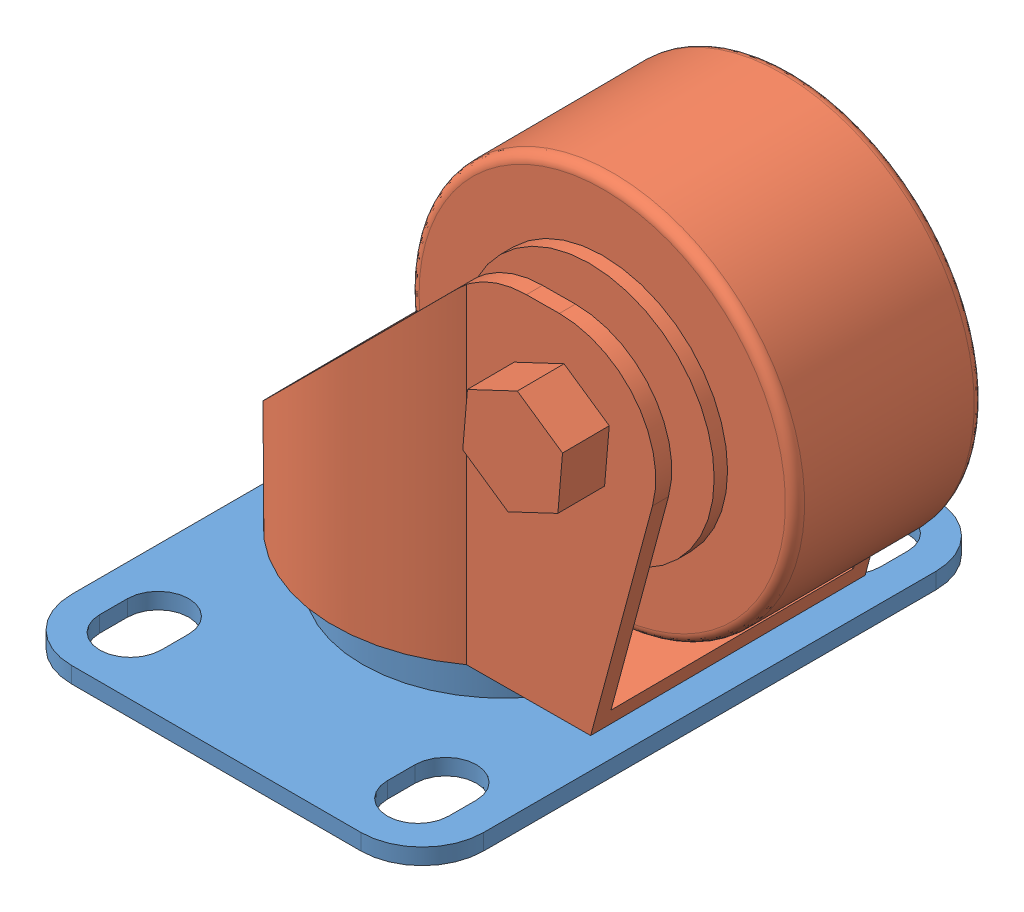
SolidWorks assembly MACM010210_UniversalWheel, configuration 默认. Lengths in mm.
Overall size (61.61 53.2 60).
2 component instances, 2 part files, 2 mates.
Components (placement in the parent):
- MACM010211_UniversalWheelA_1.5inch-1: MACM010211_UniversalWheelA_1.5inch [默认] at (-2.179 -1.6848 60) size (43 6.68 60)
- MACM010212_UniversalWheelB_1.5inch-1: MACM010212_UniversalWheelB_1.5inch [默认] at (-2.179 -1.6848 60) x (-0.005663 0 -0.999984) z (0.999984 0 -0.005663) size (38.6 46.52 57.75)
Mates (geometry in assembly coordinates):
- 重合1: coincident anti-aligned: plane of MACM010211_UniversalWheelA_1.5inch-1 through (-2.179 4.9952 60) normal (0 1 0); plane of MACM010212_UniversalWheelB_1.5inch-1 through (-2.179 4.9952 60) normal (0 -1 0)
- 同心1: concentric aligned: cylinder of MACM010211_UniversalWheelA_1.5inch-1 through (-2.179 4.9952 60) axis (0 -1 0) radius 14.75; cylinder of MACM010212_UniversalWheelB_1.5inch-1 through (-2.179 6.6752 60) axis (0 -1 0) radius 17.75
